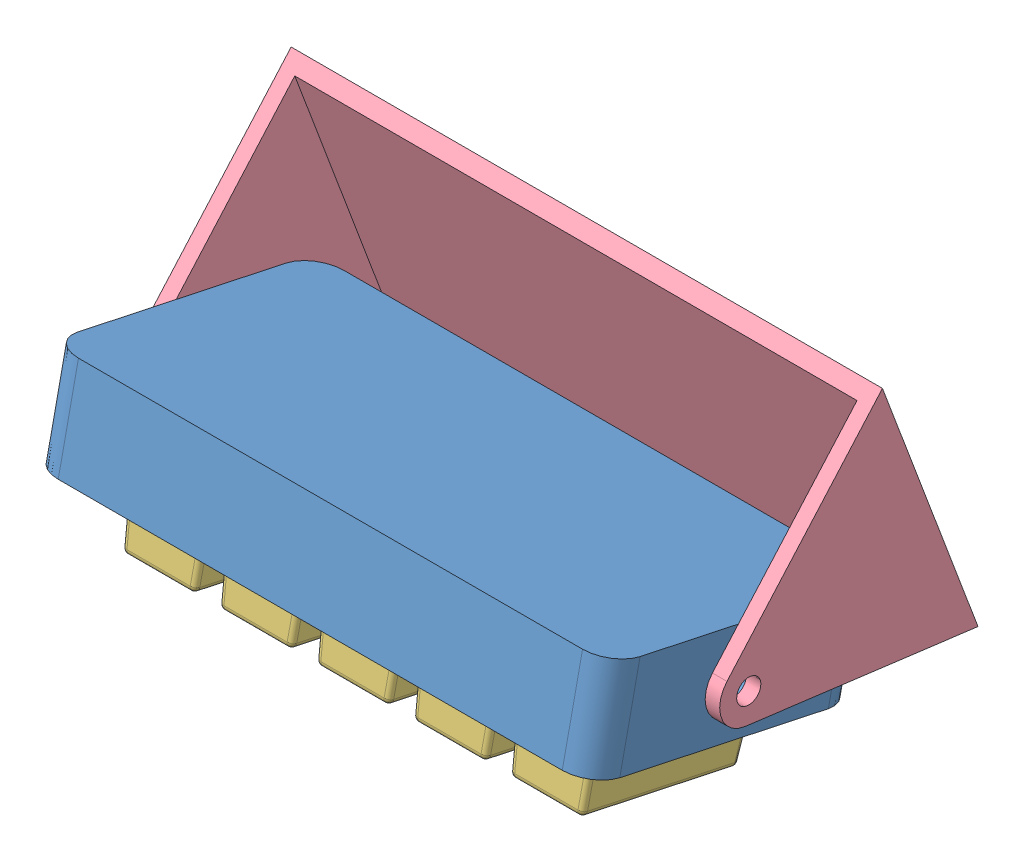
SolidWorks assembly Assemblage, configuration Défaut. Lengths in mm.
Overall size (122 68.61 76.77).
8 component instances, 4 part files, 8 mates.
Components (placement in the parent):
- corps-1: corps [Défaut] at (-11.1134 8.4755 103.7547) x (1 0 0) z (0 -0.977957 0.208807) size (116 56 20)
- face_boutons-1: face_boutons [Défaut] at (-11.1134 -8.1498 107.3044) x (1 0 0) z (0 -0.977957 0.208807) size (110 50 4)
- touche-1: touche [Défaut] at (-51.1134 -14.0175 108.5573) x (1 0 0) z (0 -0.977957 0.208807) size (16 34 10)
- touche-2: touche [Défaut] at (-31.1134 -14.0175 108.5573) x (1 0 0) z (0 -0.977957 0.208807) size (16 34 10)
- touche-3: touche [Défaut] at (-11.1134 -14.0175 108.5573) x (1 0 0) z (0 -0.977957 0.208807) size (16 34 10)
- touche-4: touche [Défaut] at (8.8866 -14.0175 108.5573) x (1 0 0) z (0 -0.977957 0.208807) size (16 34 10)
- touche-5: touche [Défaut] at (28.8866 -14.0175 108.5573) x (1 0 0) z (0 -0.977957 0.208807) size (16 34 10)
- pieds-1: pieds [Défaut] at (-11.1134 12.778 68.4036) x (0 -0.93598 -0.352052) z (-1 0 0) size (56 46 122)
Mates (geometry in assembly coordinates):
- Coïncidente1: coincident anti-aligned: plane of corps-1 through (-11.1134 -8.1498 107.3044) normal (0 -0.977957 0.208807); plane of face_boutons-1 through (-11.1134 -8.1498 107.3044) normal (0 0.977957 -0.208807)
- Coïncidente2: coincident anti-aligned: plane of corps-1 through (-69.1134 -16.3038 83.4819) normal (0 0.208807 0.977957); plane of face_boutons-1 through (43.8866 -17.2817 83.6907) normal (0 -0.208807 -0.977957)
- Coïncidente3: coincident anti-aligned: plane of corps-1 through (43.8866 -5.237 135.3136) normal (-1 0 0); plane of face_boutons-1 through (43.8866 -17.2817 83.6907) normal (1 0 0)
- Coïncidente4: coincident anti-aligned: plane of face_boutons-1 through (-11.1134 -8.1498 107.3044) normal (0 -0.208807 -0.977957); plane of touche-1 through (-51.1134 -14.0175 108.5573) normal (0 0.208807 0.977957)
- Coïncidente5: coincident anti-aligned: plane of face_boutons-1 through (-51.1134 -8.1498 107.3044) normal (-1 0 0); plane of touche-1 through (-51.1134 -14.0175 108.5573) normal (1 0 0)
- Distance1: distance = 2 mm anti-aligned: plane of touche-1 through (-51.1134 -14.0175 108.5573) normal (0 0.977957 -0.208807); plane of face_boutons-1 through (-11.1134 -12.0616 108.1397) normal (0 -0.977957 0.208807)
- Coïncidente7: coincident anti-aligned: plane of corps-1 through (-69.1134 -5.237 135.3136) normal (-1 0 0); plane of pieds-1 through (-69.1134 22.7911 121.3161) normal (1 0 0)
- Coaxiale1: concentric anti-aligned: cylinder of corps-1 through (46.8866 -1.3041 105.8428) axis (-1 0 0) radius 2.5; cylinder of pieds-1 through (-72.1134 -1.3041 105.8428) axis (1 0 0) radius 2.5
